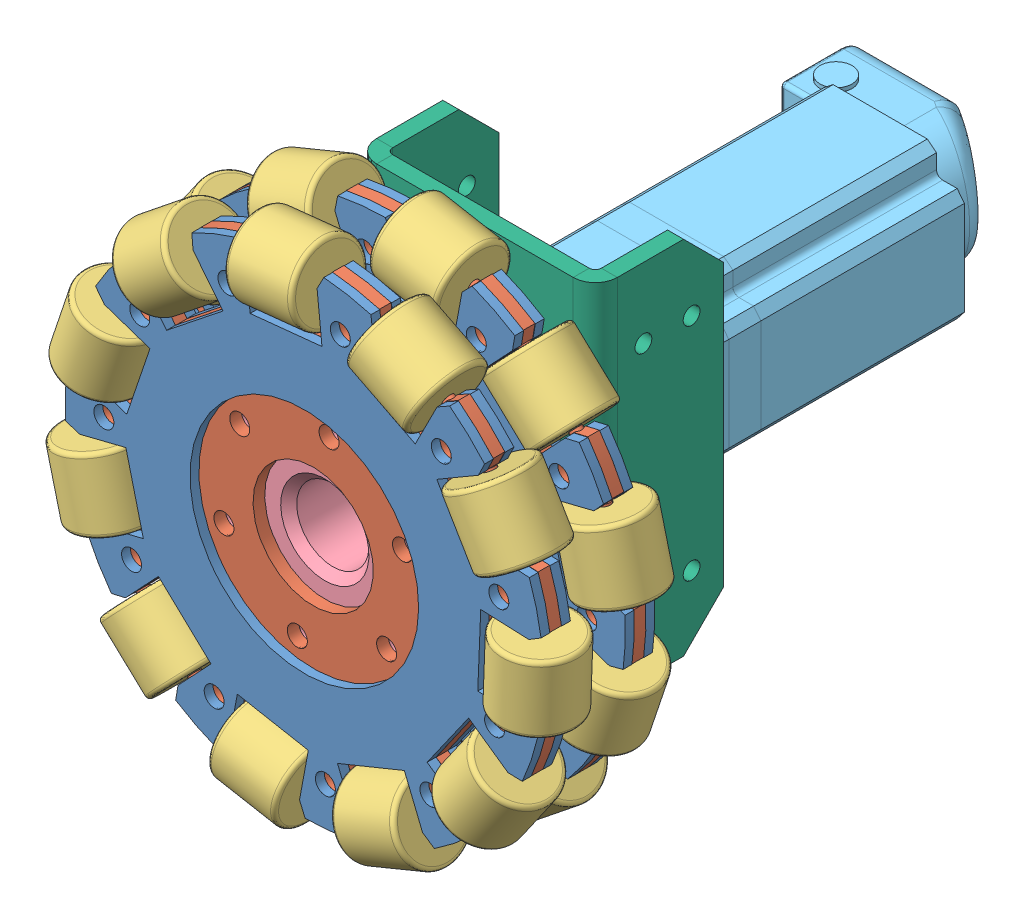
SolidWorks assembly Motor Drive_SE42, configuration 預設. Lengths in mm.
Overall size (193.52 193.52 173.24).
35 component instances, 7 part files, 11 mates.
Components (placement in the parent):
- omni wheel 127mm-1: omni wheel 127mm [預設] at (0 0 45.51) x (-0.781981 -0.623302 0) z (0 0 -1) size (147.63 147.7 47.17)
  - omni wheel 127mm 1-1: omni wheel 127mm 1 [預設] at origin size (147.34 146.72 26.77)
    - Part1-1: Part1 [Default] at (0 0 5.11) size (119.14 118.25 2.21)
    - Part3-1: Part3 [Default] at (0 0 2.21) x (0.960473 0.278374 0) z (0 0 1) size (119.14 118.23 2.9)
    - Part1-2: Part1 [Default] at origin size (119.14 118.25 2.21)
    - Part4-1: Part4 [Default] at (-22.2066 50.6262 3.66) x (0.34688 -0.54389 0.764106) z (-0.843122 -0.537723 0) size (19 19 17)
    - Part4-2: Part4 [Default] at (-46.0519 30.5837 3.66) x (0.585863 -0.270012 0.764106) z (-0.418564 -0.908187 0) size (19 19 17)
    - Part4-3: Part4 [Default] at (-55.2761 0.8311 3.66) x (0.638839 0.089593 0.764106) z (0.138884 -0.990309 0) size (19 19 17)
    - Part4-4: Part4 [Default] at (-46.9505 -29.1854 3.66) x (0.488988 0.420753 0.764106) z (0.652238 -0.758014 0) size (19 19 17)
    - Part4-5: Part4 [Default] at (-23.7185 -49.9357 3.66) x (0.183887 0.618327 0.764106) z (0.958511 -0.285056 0) size (19 19 17)
    - Part4-6: Part4 [Default] at (7.044 -54.8318 3.66) x (-0.179597 0.619586 0.764106) z (0.960463 0.278406 0) size (19 19 17)
    - Part4-7: Part4 [Default] at (35.5701 -42.3191 3.66) x (-0.48606 0.424131 0.764106) z (0.657476 0.753476 0) size (19 19 17)
    - Part4-8: Part4 [Default] at (52.8029 -16.3705 3.66) x (-0.638203 0.094018 0.764106) z (0.145744 0.989322 0) size (19 19 17)
    - Part4-9: Part4 [Default] at (53.2712 14.7757 3.66) x (-0.58772 -0.265946 0.764106) z (-0.412261 0.911066 0) size (19 19 17)
    - Part4-10: Part4 [Default] at (36.8262 41.2307 3.66) x (-0.350641 -0.541473 0.764106) z (-0.839375 0.543553 0) size (19 19 17)
    - Part4-11: Part4 [Default] at (8.6892 54.5952 3.66) x (-0.002235 -0.645087 0.764106) z (-0.999994 0.003465 0) size (19 19 17)
  - Part5-1: Part5 [Default] at (0 0 5.11) x (0.978669 -0.205441 0) z (0 0 1) size (57 57 17.5)
  - omni wheel 127mm 1-2: omni wheel 127mm 1 [預設] at (0 0 20.4) x (-1 0 0) z (0 0 1) size (147.34 146.72 26.77)
    - Part1-1: Part1 [Default] at (0 0 5.11) size (119.14 118.25 2.21)
    - Part3-1: Part3 [Default] at (0 0 2.21) x (0.960473 0.278374 0) z (0 0 1) size (119.14 118.23 2.9)
    - Part1-2: Part1 [Default] at origin size (119.14 118.25 2.21)
    - Part4-1: Part4 [Default] at (-22.2066 50.6262 3.66) x (0.34688 -0.54389 0.764106) z (-0.843122 -0.537723 0) size (19 19 17)
    - Part4-2: Part4 [Default] at (-46.0519 30.5837 3.66) x (0.585863 -0.270012 0.764106) z (-0.418564 -0.908187 0) size (19 19 17)
    - Part4-3: Part4 [Default] at (-55.2761 0.8311 3.66) x (0.638839 0.089593 0.764106) z (0.138884 -0.990309 0) size (19 19 17)
    - Part4-4: Part4 [Default] at (-46.9505 -29.1854 3.66) x (0.488988 0.420753 0.764106) z (0.652238 -0.758014 0) size (19 19 17)
    - Part4-5: Part4 [Default] at (-23.7185 -49.9357 3.66) x (0.183887 0.618327 0.764106) z (0.958511 -0.285056 0) size (19 19 17)
    - Part4-6: Part4 [Default] at (7.044 -54.8318 3.66) x (-0.179597 0.619586 0.764106) z (0.960463 0.278406 0) size (19 19 17)
    - Part4-7: Part4 [Default] at (35.5701 -42.3191 3.66) x (-0.48606 0.424131 0.764106) z (0.657476 0.753476 0) size (19 19 17)
    - Part4-8: Part4 [Default] at (52.8029 -16.3705 3.66) x (-0.638203 0.094018 0.764106) z (0.145744 0.989322 0) size (19 19 17)
    - Part4-9: Part4 [Default] at (53.2712 14.7757 3.66) x (-0.58772 -0.265946 0.764106) z (-0.412261 0.911066 0) size (19 19 17)
    - Part4-10: Part4 [Default] at (36.8262 41.2307 3.66) x (-0.350641 -0.541473 0.764106) z (-0.839375 0.543553 0) size (19 19 17)
    - Part4-11: Part4 [Default] at (8.6892 54.5952 3.66) x (-0.002235 -0.645087 0.764106) z (-0.999994 0.003465 0) size (19 19 17)
- SE42M-1: SE42M [預設] at (0 0 -4) x (0 -1 0) z (0 0 -1) size (42 46 136)
- Chassis Motor Mount-1: Chassis Motor Mount [預設] at (-3 0 0) x (0 1 0) z (0 0 1) size (90 60 32)
- 8mm Hub-1: 8mm Hub [預設] at (0 0 20) x (-0.637249 -0.770658 0) z (0 0 -1) size (56.7 56.7 15)
Mates (geometry in assembly coordinates):
- 重合/共線/共點1: coincident aligned: plane of omni wheel 127mm-1/omni wheel 127mm 1-2/Part3-1 through (-35.4421 0 20) normal (0 0 -1); circle of 8mm Hub-1
- 同軸心1: concentric anti-aligned: cylinder of omni wheel 127mm-1/omni wheel 127mm 1-2/Part1-1; cylinder of 8mm Hub-1 through (-35.4421 0 15) axis (0 0 1) radius 28.35
- 同軸心2: concentric anti-aligned: cylinder of omni wheel 127mm-1/Part5-1 through (-53.7453 15.1347 22.9) axis (0 0 1) radius 2.5; cylinder of 8mm Hub-1 through (-53.7453 15.1347 15) axis (0 0 -1) radius 2.1
- 重合/共線/共點2: coincident anti-aligned: plane of SE42M-1 through (-35.4421 0 -4) normal (0 0 1); plane of Chassis Motor Mount-1 through (-8.4421 45 -4) normal (0 0 -1)
- 同軸心3: concentric aligned: cylinder of SE42M-1 through (-35.4421 0 -1) axis (0 0 -1) radius 12.5; circle of Chassis Motor Mount-1
- 同軸心4: concentric aligned: cylinder of SE42M-1 through (-52.4127 -16.9706 -98) axis (0 0 1) radius 1.75; circle of Chassis Motor Mount-1
- 同軸心6: concentric aligned: cylinder of SE42M-1 through (-35.4421 0 18) axis (0 0 -1) radius 4; cylinder of 8mm Hub-1 through (-35.4421 0 20) axis (0 0 -1) radius 4
- 平行相距1: distance = 5 mm anti-aligned: plane of 8mm Hub-1 through (0 0 5) normal (0 0 -1); plane of Chassis Motor Mount-1 through (27 45 0) normal (0 0 1)
- 重合/共線/共點3: coincident aligned: plane of Chassis Motor Mount-1 through (-8.4421 45 0) normal (0 0 1)
- 相互對稱1: symmetric aligned: plane of SE42M-1 through (-14.4421 21 -98) normal (0 1 0); plane of SE42M-1 through (-14.4421 -21 -98) normal (0 -1 0)
- 相互對稱2: symmetric aligned: plane of SE42M-1 through (21 21 -98) normal (1 0 0); plane of SE42M-1 through (-21 21 -98) normal (-1 0 0)
